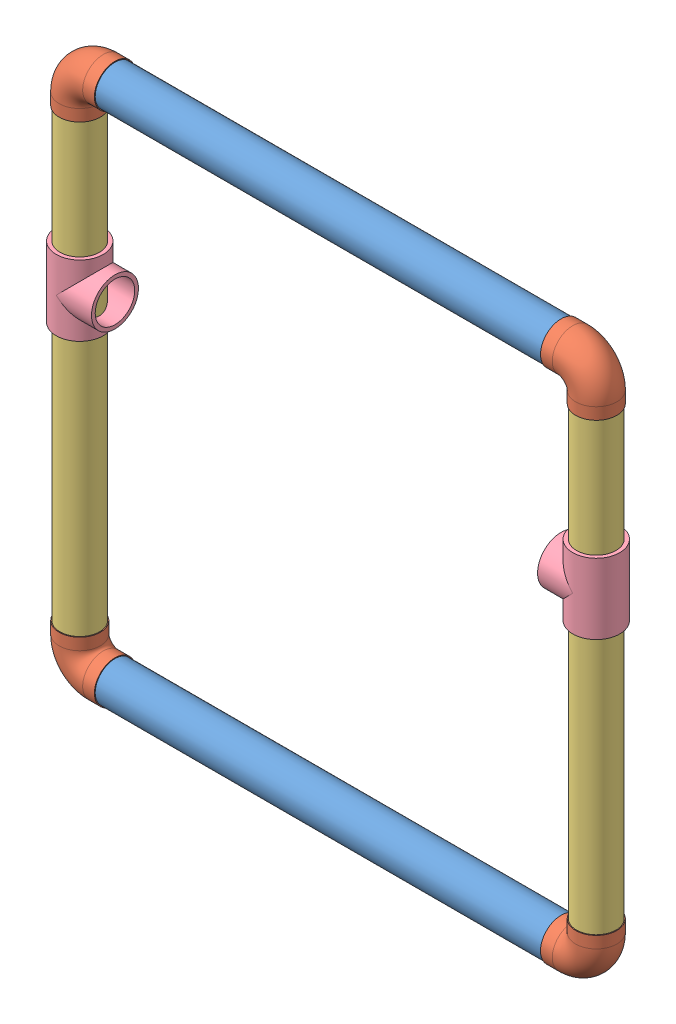
SolidWorks assembly structure_basic, configuration Default. Lengths in mm.
Overall size (304.8 301.63 25.4).
10 component instances, 4 part files, 21 mates.
Components (placement in the parent):
- PVC_tube_12in-1: PVC_tube_12in [Default] at (224.9643 139.1096 188.8412) size (254 21.34 21.34)
- PVC_90-1: PVC_90 [Default] at (-23.4538 156.2418 188.8412) size (30.16 30.16 22.23)
- PVC_90-2: PVC_90 [Default] at (220.532 157.3915 188.8412) x (0 1 0) z (0 0 1) size (30.16 30.16 22.23)
- PVC_tube_10in-1: PVC_tube_10in [Default] at (237.6643 151.8096 188.8412) x (0 -1 0) z (0 0 1) size (254 21.34 21.34)
- PVC_90-3: PVC_90 [Default] at (219.3823 401.3774 188.8412) x (-1 0 0) z (0 0 1) size (30.16 30.16 22.23)
- PVC_tube_12in-2: PVC_tube_12in [Default] at (224.9643 418.5096 188.8412) size (254 21.34 21.34)
- PVC_90-4: PVC_90 [Default] at (-24.6035 400.2277 188.8412) x (0 -1 0) z (0 0 1) size (30.16 30.16 22.23)
- PVC_tube_10in-2: PVC_tube_10in [Default] at (-41.7357 405.8096 188.8412) x (0 1 0) z (-0.97697 0 0.213378) size (254 21.34 21.34)
- PVC_tee-1: PVC_tee [Default] at (-41.7357 316.9096 188.8412) x (0 -1 0) z (0 0 1) size (38.1 38.88 25.4)
- PVC_tee-2: PVC_tee [Default] at (237.6643 316.9096 188.8412) x (0 1 0) z (0 0 1) size (38.1 38.88 25.4)
Mates (geometry in assembly coordinates):
- Concentric4: concentric aligned: cylinder of PVC_tube_12in-1 through (-29.0357 139.1096 188.8412) axis (1 0 0) radius 10.668; cylinder of PVC_90-1 through (-29.0357 139.1096 188.8412) axis (1 0 0) radius 10.6807
- Distance2: distance = 6.35 mm anti-aligned: plane of PVC_90-1 through (-22.6857 139.1096 188.8412) normal (1 0 0); plane of PVC_tube_12in-1 through (-29.0357 139.1096 188.8412) normal (-1 0 0)
- Distance3: distance = 6.35 mm anti-aligned: plane of PVC_tube_12in-1 through (224.9643 139.1096 188.8412) normal (1 0 0); plane of PVC_90-2 through (218.6143 139.1096 188.8412) normal (-1 0 0)
- Concentric11: concentric aligned: circle of PVC_tube_12in-1; circle of PVC_90-2
- Distance4: distance = 6.35 mm anti-aligned: plane of PVC_90-2 through (237.6643 158.1596 188.8412) normal (0 1 0); plane of PVC_tube_10in-1 through (237.6643 151.8096 188.8412) normal (0 -1 0)
- Concentric13: concentric anti-aligned: circle of PVC_90-2; circle of PVC_tube_10in-1
- Concentric18: concentric anti-aligned: circle of PVC_tube_10in-1; circle of PVC_90-3
- Distance6: distance = 6.35 mm anti-aligned: plane of PVC_90-3 through (237.6643 399.4596 188.8412) normal (0 -1 0); plane of PVC_tube_10in-1 through (237.6643 405.8096 188.8412) normal (0 1 0)
- Distance7: distance = 6.35 mm anti-aligned: plane of PVC_90-3 through (218.6143 418.5096 188.8412) normal (-1 0 0); plane of PVC_tube_12in-2 through (224.9643 418.5096 188.8412) normal (1 0 0)
- Concentric19: concentric anti-aligned: circle of PVC_90-3; circle of PVC_tube_12in-2
- Distance8: distance = 6.35 mm anti-aligned: plane of PVC_90-4 through (-22.6857 418.5096 188.8412) normal (1 0 0); plane of PVC_tube_12in-2 through (-29.0357 418.5096 188.8412) normal (-1 0 0)
- Concentric20: concentric anti-aligned: circle of PVC_tube_12in-2; circle of PVC_90-4
- Distance9: distance = 6.35 mm anti-aligned: plane of PVC_tube_10in-2 through (-41.7357 405.8096 188.8412) normal (0 1 0); plane of PVC_90-4 through (-41.7357 399.4596 188.8412) normal (0 -1 0)
- Concentric21: concentric anti-aligned: circle of PVC_90-4; circle of PVC_tube_10in-2
- Concentric22: concentric anti-aligned: cylinder of PVC_tube_10in-2 through (-41.7357 151.8096 188.8412) axis (0 1 0) radius 10.668; cylinder of PVC_tee-1 through (-41.7357 335.9596 188.8412) axis (0 -1 0) radius 10.6807
- Parallel13: parallel anti-aligned: plane of PVC_90-1 through (-41.7357 158.1596 188.8412) normal (0 1 0); plane of PVC_tube_10in-2 through (-41.7357 151.8096 188.8412) normal (0 -1 0)
- Distance11: distance = 63.5 mm anti-aligned: plane of PVC_90-4 through (-41.7357 399.4596 188.8412) normal (0 -1 0); plane of PVC_tee-1 through (-41.7357 335.9596 188.8412) normal (0 1 0)
- Concentric23: concentric anti-aligned: cylinder of PVC_tube_10in-1 through (237.6643 405.8096 188.8412) axis (0 -1 0) radius 10.668; cylinder of PVC_tee-2 through (237.6643 297.8596 188.8412) axis (0 1 0) radius 10.6807
- Distance12: distance = 63.5 mm anti-aligned: plane of PVC_90-3 through (237.6643 399.4596 188.8412) normal (0 -1 0); plane of PVC_tee-2 through (237.6643 335.9596 188.8412) normal (0 1 0)
- Parallel14: parallel aligned: line of PVC_tee-2 through (237.6643 316.9096 188.8412) axis (-1 0 0); line of assembly
- Coincident2: coincident anti-aligned: line of PVC_tee-1 through (-41.7357 316.9096 188.8412) axis (1 0 0); line of assembly
